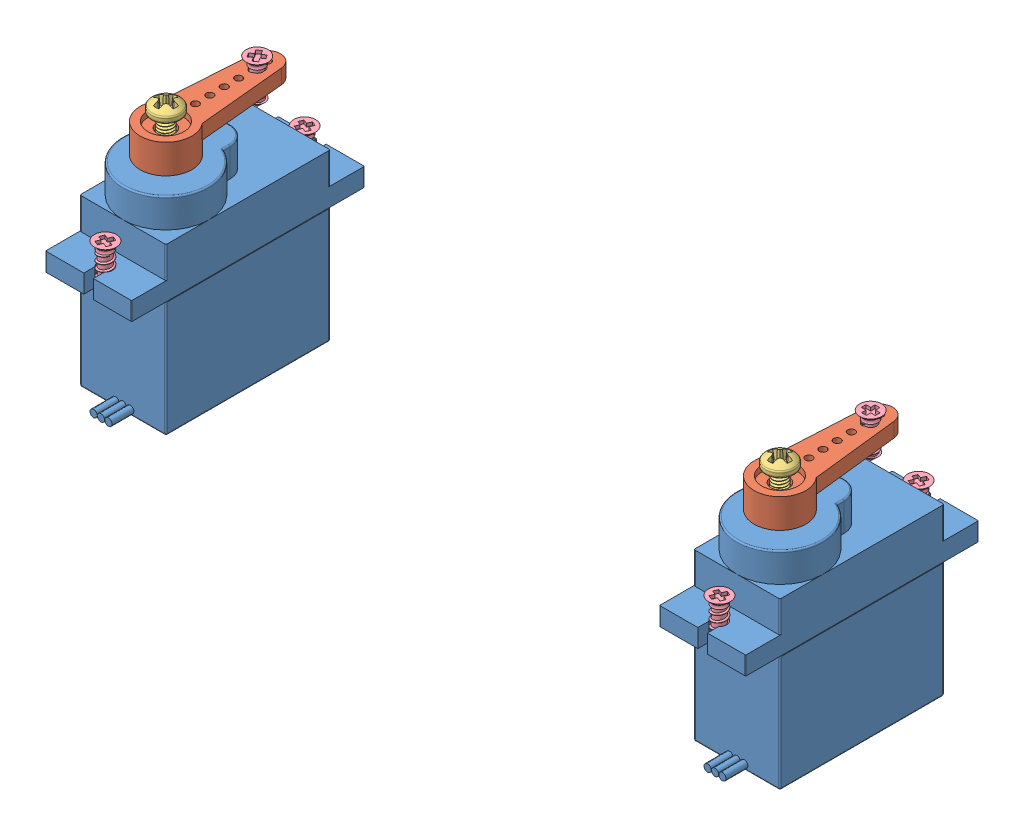
SolidWorks assembly AC, configuration Predeterminado. Lengths in mm.
Overall size (95.94 34.06 31.9).
12 component instances, 4 part files, 12 mates.
Components (placement in the parent):
- sg90-1: sg90 [Default] at (182.9409 -195.7135 134.2781) x (0 0 -1) z (1 0 0) size (31.9 29.9 11.8)
- sg90-2: sg90 [Default] at (98.7972 -195.7135 134.2781) x (0 0 -1) z (1 0 0) size (31.9 29.9 11.8)
- SG90 plastic Horn-1: SG90 plastic Horn [Default] at (188.8409 -166.2635 128.3781) x (-0.029359 0 -0.999569) z (0.999569 0 -0.029359) size (19.4 4 7.07)
- SG90 plastic Horn-2: SG90 plastic Horn [Default] at (104.6972 -166.2635 128.3781) x (-0.012387 0 -0.999923) z (0.999923 0 -0.012387) size (19.4 4 7.07)
- (M2_3_mm)_90116A007_METRIC 316 SS PAN HEAD PHILLIPS MACHINE SCREW-1: (M2_3_mm)_90116A007_METRIC 316 SS PAN HEAD PHILLIPS MACHINE SCREW [90116A007] at (104.6972 -166.2635 128.3781) x (-1 0 0) z (0 1 0) size (4 4 4.68)
- (M2_3_mm)_90116A007_METRIC 316 SS PAN HEAD PHILLIPS MACHINE SCREW-2: (M2_3_mm)_90116A007_METRIC 316 SS PAN HEAD PHILLIPS MACHINE SCREW [90116A007] at (188.8409 -166.2635 128.3781) x (-1 0 0) z (0 1 0) size (4 4 4.68)
- M2x6 SelfTap Screw-1: M2x6 SelfTap Screw [Predeterminado] at (104.6972 -162.7635 115.8781) x (0.825172 0 -0.564882) z (0 1 0) size (3.4 3.28 6)
- M2x6 SelfTap Screw-2: M2x6 SelfTap Screw [Predeterminado] at (188.7787 -162.7635 115.8783) x (0.001298 0 -0.999999) z (0 1 0) size (3.4 3.28 6)
- M2x6 SelfTap Screw-3: M2x6 SelfTap Screw [Predeterminado] at (104.6972 -174.3135 109.3781) x (-0.923728 0 -0.383049) z (0 1 0) size (3.4 3.28 6)
- M2x6 SelfTap Screw-4: M2x6 SelfTap Screw [Predeterminado] at (104.6972 -174.3135 136.6781) x (-0.923728 0 -0.383049) z (0 1 0) size (3.4 3.28 6)
- M2x6 SelfTap Screw-5: M2x6 SelfTap Screw [Predeterminado] at (188.8409 -174.3135 136.6781) x (0.923728 0 0.383049) z (0 1 0) size (3.4 3.28 6)
- M2x6 SelfTap Screw-6: M2x6 SelfTap Screw [Predeterminado] at (188.8409 -174.3135 109.3781) x (0.923728 0 0.383049) z (0 1 0) size (3.4 3.28 6)
Mates (geometry in assembly coordinates):
- Coincidente272: coincident: plane of sg90-1 through (188.8409 -165.8135 128.3781) normal (0 1 0); plane of SG90 plastic Horn-1 through (188.8043 -165.8135 127.1336) normal (0 -1 0)
- Concéntrica139: concentric: circle of sg90-1; circle of SG90 plastic Horn-1
- Concéntrica159: concentric: circle of sg90-1; circle of M2x6 SelfTap Screw-5
- Distancia35: distance = 3 mm: plane of M2x6 SelfTap Screw-5 through (188.8409 -174.3135 136.6781) normal (0 1 0); plane of sg90-1 through (182.9409 -177.3135 138.9781) normal (0 1 0)
- Concéntrica160: concentric: circle of sg90-1; circle of M2x6 SelfTap Screw-6
- Distancia36: distance = 3 mm: plane of M2x6 SelfTap Screw-6 through (188.8409 -174.3135 109.3781) normal (0 1 0); plane of sg90-1 through (194.7409 -177.3135 107.0781) normal (0 1 0)
- Coincidente273: coincident: plane of sg90-2 through (104.6972 -165.8135 128.3781) normal (0 1 0); plane of SG90 plastic Horn-2 through (104.6818 -165.8135 127.1332) normal (0 -1 0)
- Concéntrica140: concentric: circle of sg90-2; circle of SG90 plastic Horn-2
- Concéntrica161: concentric: circle of sg90-2; circle of M2x6 SelfTap Screw-4
- Distancia37: distance = 3 mm: plane of M2x6 SelfTap Screw-4 through (104.6972 -174.3135 136.6781) normal (0 1 0); plane of sg90-2 through (98.7972 -177.3135 138.9781) normal (0 1 0)
- Distancia38: distance = 3 mm: plane of M2x6 SelfTap Screw-3 through (104.6972 -174.3135 109.3781) normal (0 1 0); plane of sg90-2 through (110.5972 -177.3135 107.0781) normal (0 1 0)
- Concéntrica162: concentric: circle of sg90-2; circle of M2x6 SelfTap Screw-3
